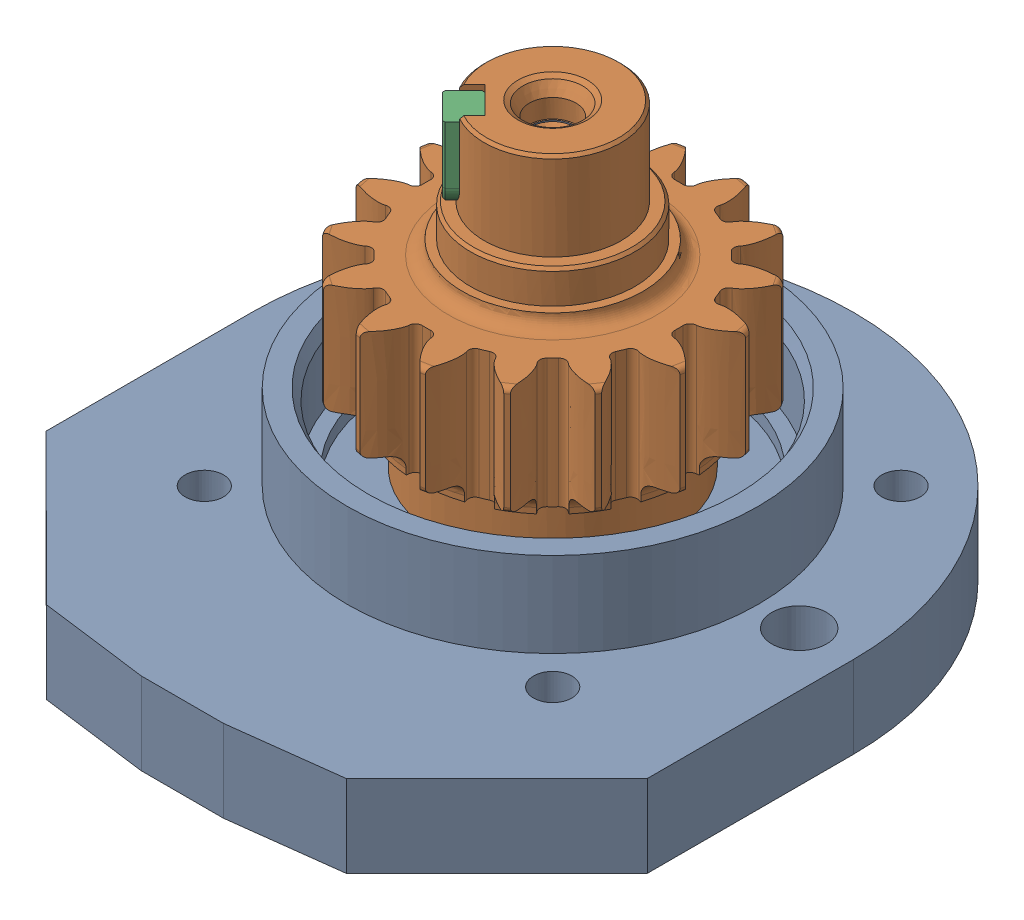
SolidWorks assembly g1_3_1_1_2_1, configuration 默认. Lengths in mm.
Overall size (219.6 152 245).
3 component instances, 3 part files, 0 mates.
Components (placement in the parent):
- g1_3_1_1_2-1_1-1: g1_3_1_1_2-1_1 [默认] at origin size (219.6 61 245)
- g1_3_1_1_2-2_1-1: g1_3_1_1_2-2_1 [默认] at (0 152 0) x (-0.047609 0 0.998866) z (0 1 0) size (120.16 120.16 117)
- g1_3_1_1_2-3_1-1: g1_3_1_1_2-3_1 [默认] at (-20.1525 129 20.1525) x (0 -1 0) z (0.707107 0 0.707107) size (28 11 14)
